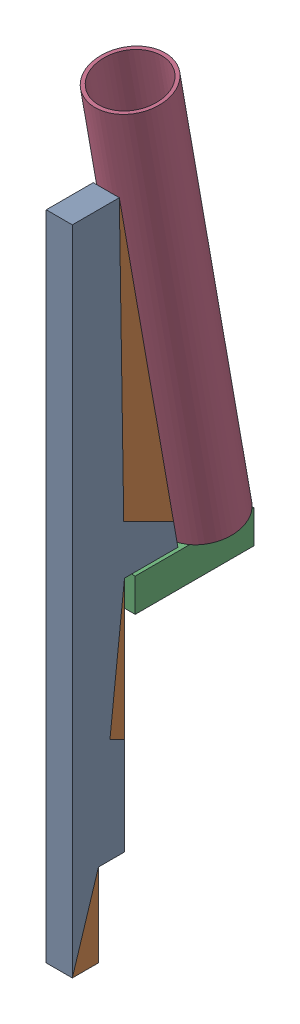
SolidWorks assembly SupportEau v9-2, configuration Défaut. Lengths in mm.
Overall size (60 625.45 150.06).
3 component instances, 3 part files, 0 mates.
Components (placement in the parent):
- SupportEau1 v7-1: SupportEau1 v7 [Défaut] at (-1368.5587 0 -111.6562) x (0 0 -1) z (0 -1 0) size (89 22 550)
- SupportEau2 v5-1: SupportEau2 v5 [Défaut] at (-1357.5587 242 -175.6562) x (0 0 -1) z (1 0 0) size (100 28 28)
- SupportEau3 v3-1: SupportEau3 v3 [Défaut] at (-1357.5587 620.2395 -171.3932) x (0 0.173648 -0.984808) z (-1 0 0) size (60 350 60)
